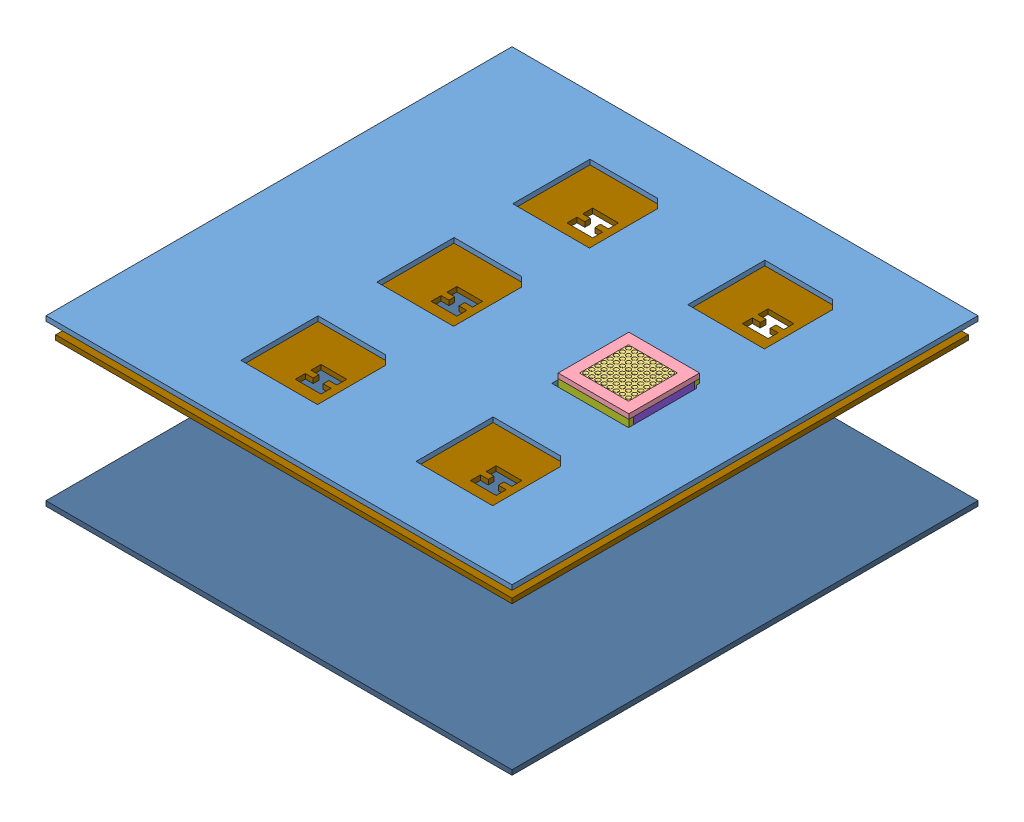
SolidWorks assembly omega3, configuration Default. Lengths in mm.
Overall size (304.8 113.81 304.8).
15 component instances, 10 part files, 5 mates.
Components (placement in the parent):
- topboard-1: topboard [Default] at (112.2319 157.0318 241.7756) size (304.8 3.17 304.8)
- cube-1: cube [Default] at (164.2192 136.6763 211.6506) size (60 36.75 46.23)
  - ledmatrixbackpack-1: ledmatrixbackpack [Default] at (-2.4215 -0.1769 -1.3195) size (39.69 12.76 33.34)
    - LEDbackpack-1: LEDbackpack [Default] at (14.4644 16.8017 31.6864) size (39.69 4.76 33.34)
    - LED Matrix-1: LED Matrix [?] at (14.2971 25.5642 31.6526) x (-1 0 0) z (0 0 -1) size (32 12.5 32)
  - cubetop-1: cubetop [Default] at (-261.361 26.2123 338.6099) size (46.23 3.17 46.23)
  - cubebottom-1: cubebottom [Default] at (-5.8761 29.2621 78.9283) x (1 0 0) z (0 0 -1) size (60 6.59 40)
    - protoboard-1: protoboard [Default] at (17.8486 30.0373 48.7812) size (60 1.59 40)
    - cubebottompins-1: cubebottompins [Default] at (18.9924 31.6248 49.6374) size (14.29 5 14.29)
  - cubeside1-1: cubeside1 [Default] at (12.0005 11.9248 50.1471) size (46.23 28.57 3.17)
  - cubeside1-2: cubeside1 [Default] at (12.0005 11.9248 7.0941) size (46.23 28.57 3.17)
  - cubeside2-1: cubeside2 [Default] at (31.9395 12.7503 30.2081) x (0 0 -1) z (1 0 0) size (39.88 26.92 3.17)
  - cubeside2-2: cubeside2 [Default] at (-7.9385 12.7503 30.2081) x (0 0 1) z (-1 0 0) size (39.88 26.92 3.17)
- middleboard-1: middleboard [Default] at (99.6918 146.2516 241.7756) size (298.45 3.17 298.45)
- base-1: base [Default] at (99.6918 55.4318 241.7756) x (1 0 0) z (0 -1 0) size (304.8 304.8 3.17)
Mates (geometry in assembly coordinates):
- Distance1: distance = 3.175 mm aligned: plane of middleboard-1 through (-49.5332 149.4266 92.5506) normal (0 0 -1); plane of topboard-1 through (-52.7082 160.2068 89.3756) normal (0 0 -1)
- Distance2: distance = 3.175 mm: plane of middleboard-1 through (248.9168 149.4266 391.0006) normal (1 0 0); line of topboard-1 through (252.0918 160.2068 394.1756) axis (0 0 -1)
- Coincident1: coincident: plane of topboard-1 through (-52.7082 160.2068 89.3756) normal (0 0 -1); plane of base-1 through (-52.7082 130.9892 89.3756) normal (0 0 -1)
- Coincident2: coincident: plane of topboard-1 through (-52.7082 160.2068 394.1756) normal (-1 0 0); plane of base-1 through (-52.7082 130.9892 89.3756) normal (-1 0 0)
- Distance5: distance = 101.6 mm anti-aligned: plane of topboard-1 through (112.2319 157.0318 241.7756) normal (0 -1 0); plane of base-1 through (99.6918 55.4318 241.7756) normal (0 1 0)
